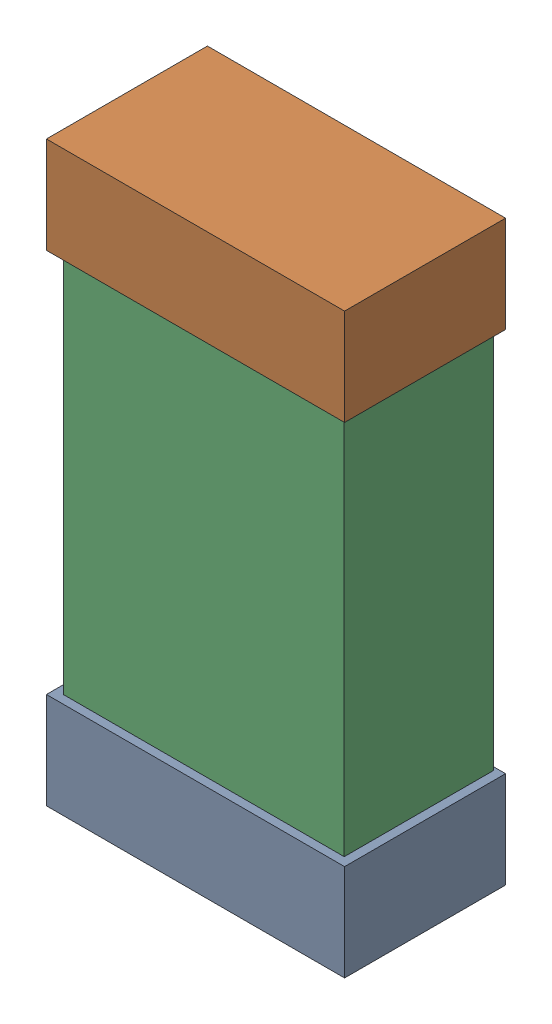
SolidWorks assembly C7, configuration Default. Lengths in mm.
Overall size (0.85 1.65 0.46).
6 component instances, 2 part files, 0 mates.
Components (placement in the parent):
- 432138512-1: 432138512 [Default] at (38.2832 29.7134 -0.8715) size (0.85 0.28 0.46)
  - Extruded-1: Extruded [Default] at origin size (0.85 0.28 0.46)
- 432138512_1-1: 432138512_1 [Default] at (38.2832 31.0849 -0.8715) size (0.85 0.28 0.46)
  - Extruded-1: Extruded [Default] at origin size (0.85 0.28 0.46)
- 432124816-1: 432124816 [Default] at (38.2832 30.3991 -0.8615) size (0.8 1.5 0.42)
  - Extruded (1)-1: Extruded (1) [Default] at origin size (0.8 1.5 0.42)
